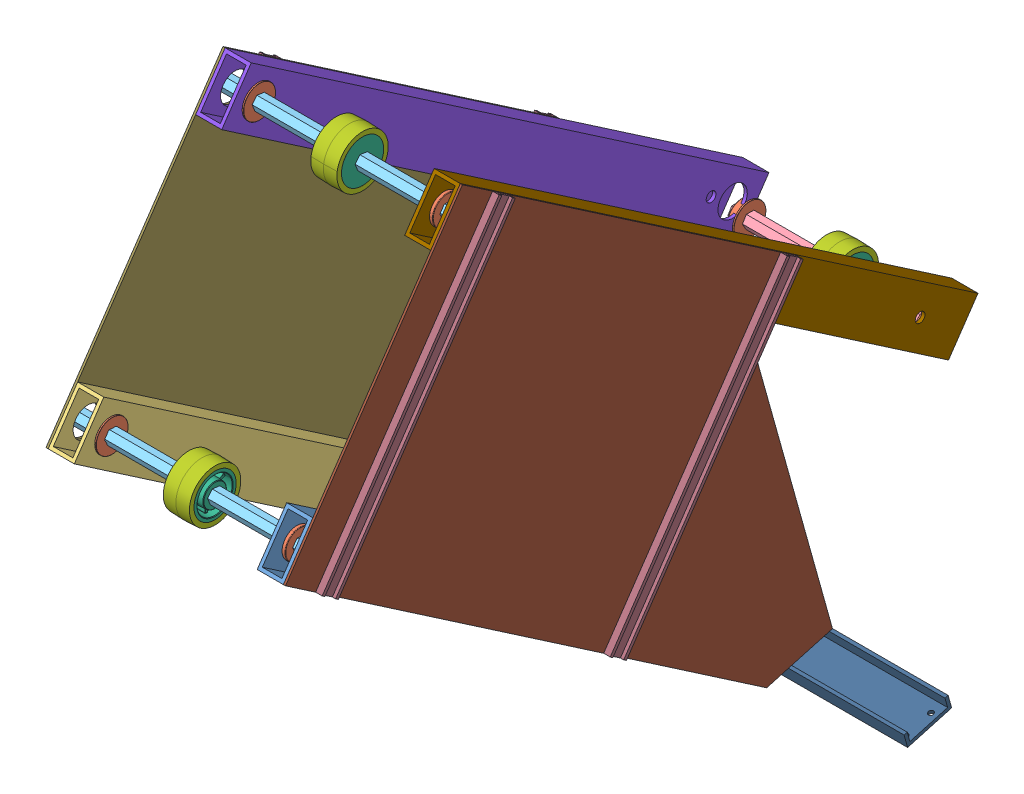
SolidWorks assembly Indexer, configuration Default. Lengths in mm.
Overall size (457.2 595.62 692.82).
37 component instances, 13 part files, 40 mates.
Components (placement in the parent):
- Bottom Indexer-1: Bottom Indexer [Default] at (229.7718 335.1654 356.4707) size (241.3 388.75 534.78)
  - Bottom Box Bar-1: Bottom Box Bar [Default] at (679.4899 930.1324 1666.1793) x (0 -0.825583 0.564281) z (0 -0.564281 -0.825583) size (50.8 25.4 609.6)
  - am-2986 FR8ZZ Hex Bearing.step-3: am-2986 FR8ZZ Hex Bearing.step [Default] at (660.4933 614.1774 1248.9284) x (0 0 1) z (-1 0 0) size (31.12 31.12 7.93)
  - am-2986 FR8ZZ Hex Bearing.step-4: am-2986 FR8ZZ Hex Bearing.step [Default] at (660.4933 894.8298 1659.5422) x (0 -0.924225 -0.381849) z (-1 0 0) size (31.12 31.12 7.93)
  - Bottom Box Bar B-1: Bottom Box Bar B [Default] at (476.2899 930.1324 1666.1793) x (0 -0.825583 0.564281) z (0 -0.564281 -0.825583) size (50.8 25.4 609.6)
  - am-2986 FR8ZZ Hex Bearing.step-9: am-2986 FR8ZZ Hex Bearing.step [Default] at (469.8866 894.8298 1659.5422) x (0 0 -1) z (1 0 0) size (31.12 31.12 7.93)
  - am-2986 FR8ZZ Hex Bearing.step-10: am-2986 FR8ZZ Hex Bearing.step [Default] at (469.8866 614.1774 1248.9284) x (0 0 -1) z (1 0 0) size (31.12 31.12 7.93)
  - bottom second rod-1: bottom second rod [Default] at (463.5899 614.1774 1248.9284) x (1 0 0) z (0 -0.866025 -0.5) size (203.2 12.7 14.66)
  - bottom first rod-2: bottom first rod [Default] at (438.1899 894.8298 1659.5422) x (1 0 0) z (0 -0.792804 0.609477) size (228.6 12.7 14.66)
  - am-3155 2IN 500Hex Stealth Wheel REV2.STEP-1: am-3155 2IN 500Hex Stealth Wheel REV2.STEP [Default] at (552.4899 606.4819 1277.5388) x (0 0.866025 -0.5) z (-1 0 0) size (57.25 57.25 25.4)
    - 2in Wheel Intergrated 0500 HEX Hub.STEP-1: 2in Wheel Intergrated 0500 HEX Hub.STEP [Default] at (20.955 20.955 -12.7) x (-0.866025 0.5 0) z (0 0 -1) size (41.91 41.91 25.4)
    - 2in Tread.STEP-1: 2in Tread.STEP [Default] at (20.955 20.955 -12.7) x (0 0 -1) z (1 0 0) size (25.4 50.8 50.8)
  - am-3155 2IN 500Hex Stealth Wheel REV2.STEP-2: am-3155 2IN 500Hex Stealth Wheel REV2.STEP [Default] at (577.8899 924.2456 1663.4241) x (0 -0.792804 0.609477) z (1 0 0) size (57.25 57.25 25.4)
    - 2in Wheel Intergrated 0500 HEX Hub.STEP-1: 2in Wheel Intergrated 0500 HEX Hub.STEP [Default] at (20.955 20.955 -12.7) x (-0.866025 0.5 0) z (0 0 -1) size (41.91 41.91 25.4)
    - 2in Tread.STEP-1: 2in Tread.STEP [Default] at (20.955 20.955 -12.7) x (0 0 -1) z (1 0 0) size (25.4 50.8 50.8)
- Top Box Bar-1: Top Box Bar [Default] at (706.0617 1474.9957 1879.3225) x (0 -0.825583 0.564281) z (0 -0.564281 -0.825583) size (50.8 25.4 609.6)
- Top Box Bar B-1: Top Box Bar B [Default] at (909.2617 1474.9957 1879.3225) x (0 -0.825583 0.564281) z (0 -0.564281 -0.825583) size (50.8 25.4 609.6)
- Indexer Bottom Bar-1: Indexer Bottom Bar [Default] at (566.3617 897.0934 1558.7521) x (1 0 0) z (0 -0.26972 0.962939) size (457.2 12.7 44.45)
- Top Indexer-1: Top Indexer [Default] at (0 -31.4192 24.5795) x (1 0 0) z (0 0.016887 0.999857) size (228.6 390.37 543.04)
  - am-2986 FR8ZZ Hex Bearing.step-1: am-2986 FR8ZZ Hex Bearing.step [Default] at (699.6584 1110.04 1390.3802) x (0 0 -1) z (1 0 0) size (31.12 31.12 7.93)
  - am-2986 FR8ZZ Hex Bearing.step-2: am-2986 FR8ZZ Hex Bearing.step [Default] at (890.265 1110.04 1390.3802) x (0 0 1) z (-1 0 0) size (31.12 31.12 7.93)
  - am-2986 FR8ZZ Hex Bearing.step-3: am-2986 FR8ZZ Hex Bearing.step [Default] at (699.6584 1439.6932 1872.6855) x (0 -0.924225 -0.381849) z (1 0 0) size (31.12 31.12 7.93)
  - am-2986 FR8ZZ Hex Bearing.step-4: am-2986 FR8ZZ Hex Bearing.step [Default] at (890.265 1439.6932 1872.6855) x (0 0 1) z (-1 0 0) size (31.12 31.12 7.93)
  - bottom first rod-1: bottom first rod [Default] at (667.9617 1439.6932 1872.6855) x (1 0 0) z (0 -0.924225 -0.381849) size (228.6 12.7 14.66)
  - bottom second rod-1: bottom second rod [Default] at (693.3617 1110.04 1390.3802) x (1 0 0) z (0 -0.866025 -0.5) size (203.2 12.7 14.66)
  - am-3155 2IN 500Hex Stealth Wheel REV2.STEP-1: am-3155 2IN 500Hex Stealth Wheel REV2.STEP [Default] at (782.2617 1131.0204 1411.3792) x (0 0 -1) z (-1 0 0) size (57.25 57.25 25.4)
    - 2in Wheel Intergrated 0500 HEX Hub.STEP-1: 2in Wheel Intergrated 0500 HEX Hub.STEP [Default] at (20.955 20.955 -12.7) x (-0.866025 0.5 0) z (0 0 -1) size (41.91 41.91 25.4)
    - 2in Tread.STEP-1: 2in Tread.STEP [Default] at (20.955 20.955 -12.7) x (0 0 -1) z (1 0 0) size (25.4 50.8 50.8)
  - am-3155 2IN 500Hex Stealth Wheel REV2.STEP-2: am-3155 2IN 500Hex Stealth Wheel REV2.STEP [Default] at (782.2617 1463.1971 1890.7227) x (0 -0.131421 -0.991327) z (-1 0 0) size (57.25 57.25 25.4)
    - 2in Wheel Intergrated 0500 HEX Hub.STEP-1: 2in Wheel Intergrated 0500 HEX Hub.STEP [Default] at (20.955 20.955 -12.7) x (-0.866025 0.5 0) z (0 0 -1) size (41.91 41.91 25.4)
    - 2in Tread.STEP-1: 2in Tread.STEP [Default] at (20.955 20.955 -12.7) x (0 0 -1) z (1 0 0) size (25.4 50.8 50.8)
- Indexer Side Wall-1: Indexer Side Wall [Default] at (909.2617 1265.2977 2022.65) x (0 0.825583 -0.564281) z (1 0 0) size (304.8 609.3 2.11)
- Indexer Side Wall B-1: Indexer Side Wall B [Default] at (678.5535 1265.2977 2022.65) x (0 0.825583 -0.564281) z (1 0 0) size (304.8 609.6 2.11)
- Connecting Bar-1: Connecting Bar [Default] at (911.3699 1263.5877 1570.018) x (0 -0.564281 -0.825583) z (0 -0.825583 0.564281) size (19.05 6.35 304.8)
- Connecting Bar-2: Connecting Bar [Default] at (678.5535 1252.8381 1554.2907) x (0 0.564281 0.825583) z (0 -0.825583 0.564281) size (19.05 6.35 304.8)
- Connecting Bar-3: Connecting Bar [Default] at (911.3699 1454.9728 1850.0276) x (0 -0.564281 -0.825583) z (0 -0.825583 0.564281) size (19.05 6.35 304.8)
- Connecting Bar-4: Connecting Bar [Default] at (678.5535 1435.5807 1821.6556) x (0 0.564281 0.825583) z (0 -0.825583 0.564281) size (19.05 6.35 304.8)
Mates (geometry in assembly coordinates):
- Coincident2: coincident aligned: plane of Bottom Indexer-1/Bottom Box Bar B-1 through (706.0617 921.3118 1519.3749) normal (1 0 0); plane of Top Box Bar-1 through (706.0617 1131.0098 1376.0474) normal (1 0 0)
- Distance1: distance = 203.2 mm: line of Bottom Indexer-1/Bottom Box Bar B-1 through (706.0617 921.3118 1519.3749) axis (0 0.564281 0.825583); line of Top Box Bar-1 through (706.0617 1089.0702 1404.7129) axis (0 0.564281 0.825583)
- Coincident4: coincident aligned: plane of Top Box Bar-1 through (706.0617 1131.0098 1376.0474) normal (0 0.825583 -0.564281); plane of Top Box Bar B-1 through (909.2617 1131.0098 1376.0474) normal (0 0.825583 -0.564281)
- Coincident6: coincident aligned: plane of Bottom Indexer-1/Bottom Box Bar-1 through (909.2617 921.3118 1519.3749) normal (1 0 0); plane of Top Box Bar B-1 through (909.2617 1131.0098 1376.0474) normal (1 0 0)
- Width1: width anti-aligned: plane of Indexer Bottom Bar-1 through (1023.5617 897.0934 1558.7521) normal (1 0 0); plane of Indexer Bottom Bar-1 through (566.3617 897.0934 1558.7521) normal (-1 0 0); plane of Bottom Indexer-1/Bottom Box Bar B-1 through (680.6617 921.3118 1519.3749) normal (-1 0 0); plane of Bottom Indexer-1/Bottom Box Bar-1 through (909.2617 921.3118 1519.3749) normal (1 0 0)
- Coincident9: coincident aligned: plane of Bottom Indexer-1/Bottom Box Bar-1 through (909.2617 1265.2977 2022.65) normal (0 0.564281 0.825583); plane of Top Box Bar B-1 through (909.2617 1474.9957 1879.3225) normal (0 0.564281 0.825583)
- InPlace1: in place: plane of Bottom Indexer-1/Bottom Box Bar-1 through (909.2617 921.3118 1519.3749) normal (1 0 0); plane of ? through (909.2617 0 0) normal (1 0 0); moOrthogonalPlaneRef_w of Bottom Indexer-1/Bottom Box Bar-1 through (909.2617 921.3118 1519.3749) normal (1 0 0); plane of ? through (909.2617 0 0) normal (0 1 0); plane of Bottom Indexer-1/Bottom Box Bar-1 through (909.2617 921.3118 1519.3749) normal (1 0 0); plane of ? through (909.2617 0 0) normal (0 0 -1); plane of Bottom Indexer-1/Bottom Box Bar-1 through (909.2617 921.3118 1519.3749) normal (1 0 0); unknown of Indexer Side Wall-1
- Coincident26: coincident aligned: plane of Bottom Indexer-1/Bottom Box Bar-1; plane of Indexer Side Wall-1
- Coincident27: coincident aligned: moOrthogonalPlaneRef_w of Bottom Indexer-1/Bottom Box Bar-1 through (909.2617 1265.2977 2022.65) normal (0 0.564281 0.825583); plane of Indexer Side Wall-1 through (909.2617 1265.2977 2022.65) normal (0 0.564281 0.825583)
- Coincident28: coincident anti-aligned: moOrthogonalPlaneRef_w of Bottom Indexer-1/Bottom Box Bar-1 through (909.2617 1265.2977 2022.65) normal (0 -0.825583 0.564281); plane of Indexer Side Wall-1 through (909.2617 1265.2977 2022.65) normal (0 0.825583 -0.564281)
- Coincident29: coincident anti-aligned: line of Bottom Indexer-1/Bottom Box Bar B-1 through (680.6617 903.4254 1583.2319) axis (0 0.564281 0.825583); line of Indexer Side Wall B-1 through (680.6617 1223.3581 2051.3155) axis (0 -0.564281 -0.825583)
- Coincident30: coincident anti-aligned: line of Bottom Indexer-1/Bottom Box Bar B-1 through (680.6617 1223.3581 2051.3155) axis (0 0.825583 -0.564281); line of Indexer Side Wall B-1 through (680.6617 1474.9957 1879.3225) axis (0 -0.825583 0.564281)
- Coincident32: coincident anti-aligned: line of Indexer Side Wall B-1 through (678.5535 1223.3581 2051.3155) axis (0 -0.564281 -0.825583); line of Connecting Bar-4 through (678.5535 1183.9431 1993.6486) axis (0 0.564281 0.825583)
- Coincident33: coincident anti-aligned: line of Indexer Side Wall B-1 through (678.5535 1223.3581 2051.3155) axis (0 -0.564281 -0.825583); line of Connecting Bar-2 through (678.5535 1001.2006 1726.2837) axis (0 0.564281 0.825583)
- Coincident34: coincident anti-aligned: plane of Indexer Side Wall B-1 through (678.5535 1265.2977 2022.65) normal (-1 0 0); plane of Connecting Bar-4 through (678.5535 1183.9431 1993.6486) normal (1 0 0)
- Coincident36: coincident anti-aligned: plane of Indexer Side Wall B-1 through (678.5535 1265.2977 2022.65) normal (-1 0 0); plane of Connecting Bar-2 through (678.5535 1001.2006 1726.2837) normal (1 0 0)
- Distance2: distance = 50.8 mm aligned: plane of Connecting Bar-4 through (678.5535 1194.6927 2009.3759) normal (0 0.564281 0.825583); plane of Top Box Bar-1 through (706.0617 1474.9957 1879.3225) normal (0 0.564281 0.825583)
- Distance3: distance = 215.9 mm aligned: plane of Connecting Bar-2 through (678.5535 1001.2006 1726.2837) normal (0 -0.564281 -0.825583); plane of Top Box Bar-1 through (706.0617 1131.0098 1376.0474) normal (0 -0.564281 -0.825583)
- Coincident39: coincident anti-aligned: plane of Indexer Side Wall-1 through (911.3699 1265.2977 2022.65) normal (1 0 0); plane of Connecting Bar-1 through (911.3699 1011.9501 1742.011) normal (-1 0 0)
- Coincident40: coincident anti-aligned: plane of Indexer Side Wall-1 through (911.3699 1265.2977 2022.65) normal (1 0 0); plane of Connecting Bar-3 through (911.3699 1203.3352 2022.0206) normal (-1 0 0)
- Coincident41: coincident aligned: line of Indexer Side Wall-1 through (911.3699 1223.3581 2051.3155) axis (0 -0.564281 -0.825583); line of Connecting Bar-3 through (911.3699 1203.3352 2022.0206) axis (0 -0.564281 -0.825583)
- Coincident42: coincident aligned: line of Indexer Side Wall-1 through (911.3699 1223.3581 2051.3155) axis (0 -0.564281 -0.825583); line of Connecting Bar-1 through (911.3699 1011.9501 1742.011) axis (0 -0.564281 -0.825583)
- Coincident44: coincident aligned: plane of Connecting Bar-1 through (911.3699 1011.9501 1742.011) normal (0 0.564281 0.825583); plane of Connecting Bar-2 through (678.5535 1011.9501 1742.011) normal (0 0.564281 0.825583)
- Coincident45: coincident anti-aligned: plane of Top Box Bar-1 through (706.0617 1131.0098 1376.0474) normal (1 0 0); plane of Top Indexer-1/am-2986 FR8ZZ Hex Bearing.step-1 through (706.0617 1101.7063 1382.0479) normal (-1 0 0)
- Coincident48: coincident anti-aligned: plane of Top Box Bar B-1 through (883.8617 1131.0098 1376.0474) normal (-1 0 0); plane of Top Indexer-1/am-2986 FR8ZZ Hex Bearing.step-2 through (883.8617 1102.1781 1409.9839) normal (1 0 0)
- Concentric7: concentric aligned: cylinder of Top Box Bar-1 through (706.0617 1439.6932 1872.6855) axis (-1 0 0) radius 14.2875; cylinder of Top Indexer-1/am-2986 FR8ZZ Hex Bearing.step-3 through (707.5857 1439.6932 1872.6855) axis (-1 0 0) radius 14.2875
- Coincident49: coincident anti-aligned: plane of Top Box Bar-1 through (706.0617 1131.0098 1376.0474) normal (1 0 0); plane of Top Indexer-1/am-2986 FR8ZZ Hex Bearing.step-3 through (706.0617 1426.6935 1867.5699) normal (-1 0 0)
- Concentric8: concentric anti-aligned: cylinder of Top Box Bar B-1 through (887.0367 1439.6932 1872.6855) axis (-1 0 0) radius 14.2875; cylinder of Top Indexer-1/am-2986 FR8ZZ Hex Bearing.step-4 through (882.3377 1439.6932 1872.6855) axis (1 0 0) radius 14.2875
- Coincident52: coincident anti-aligned: plane of Top Box Bar B-1 through (883.8617 1131.0098 1376.0474) normal (-1 0 0); plane of Top Indexer-1/am-2986 FR8ZZ Hex Bearing.step-4 through (883.8617 1439.9291 1886.6535) normal (1 0 0)
- Width4: width anti-aligned: plane of Top Indexer-1/bottom second rod-1 through (896.5617 1101.9422 1396.0159) normal (1 0 0); plane of Top Indexer-1/bottom second rod-1 through (693.3617 1101.9422 1396.0159) normal (-1 0 0); plane of Top Box Bar-1 through (680.6617 1131.0098 1376.0474) normal (-1 0 0); plane of Top Box Bar B-1 through (909.2617 1131.0098 1376.0474) normal (1 0 0)
- Width5: width anti-aligned: plane of Top Indexer-1/am-3155 2IN 500Hex Stealth Wheel REV2.STEP-1/2in Tread.STEP-1 through (807.6617 1077.0154 1396.4809) normal (1 0 0); plane of Top Indexer-1/am-3155 2IN 500Hex Stealth Wheel REV2.STEP-1/2in Tread.STEP-1 through (782.2617 1077.0154 1396.4809) normal (-1 0 0); plane of Top Box Bar B-1 through (883.8617 1131.0098 1376.0474) normal (-1 0 0); plane of Top Box Bar-1 through (706.0617 1131.0098 1376.0474) normal (1 0 0)
- Coincident53: coincident aligned: plane of Bottom Indexer-1/Bottom Box Bar B-1 through (706.0617 921.3118 1519.3749) normal (1 0 0); plane of Top Indexer^Indexer-1/Top Box Bar-1 through (706.0617 1116.677 1355.0776) normal (1 0 0)
- Distance5: distance = 203.2 mm: line of Bottom Indexer-1/Bottom Box Bar B-1 through (706.0617 921.3118 1519.3749) axis (0 0.564281 0.825583); line of Top Indexer^Indexer-1/Top Box Bar-1 through (706.0617 1074.7374 1383.7431) axis (0 0.564281 0.825583)
- Coincident54: coincident aligned: plane of Top Indexer^Indexer-1/Top Box Bar-1 through (706.0617 1116.677 1355.0776) normal (0 0.825583 -0.564281); plane of Top Box Bar B-1 through (909.2617 1131.0098 1376.0474) normal (0 0.825583 -0.564281)
- Coincident55: coincident aligned: plane of Top Indexer^Indexer-1/Top Box Bar-1 through (706.0617 1116.677 1355.0776) normal (0 -0.564281 -0.825583); plane of Top Box Bar B-1 through (909.2617 1131.0098 1376.0474) normal (0 -0.564281 -0.825583)
- Distance6: distance = 50.8 mm aligned: plane of Connecting Bar-4 through (678.5535 1194.6927 2009.3759) normal (0 0.564281 0.825583); plane of Top Indexer^Indexer-1/Top Box Bar-1 through (706.0617 1474.9957 1879.3225) normal (0 0.564281 0.825583)
- Distance7: distance = 215.9 mm aligned: plane of Connecting Bar-2 through (678.5535 1001.2006 1726.2837) normal (0 -0.564281 -0.825583); plane of Top Indexer^Indexer-1/Top Box Bar-1 through (706.0617 1116.677 1355.0776) normal (0 -0.564281 -0.825583)
- Coincident56: coincident anti-aligned: line of Bottom Indexer-1/Bottom Box Bar-1 through (883.8617 921.3118 1519.3749) axis (1 0 0); line of Indexer Bottom Bar-1 through (1023.5617 921.3118 1519.3749) axis (-1 0 0)
- Coincident57: coincident anti-aligned: plane of Bottom Indexer-1/Bottom Box Bar B-1 through (706.0617 903.4254 1583.2319) normal (0 -0.962939 -0.26972); plane of Indexer Bottom Bar-1 through (1023.5617 909.3228 1562.1775) normal (0 0.962939 0.26972)
- Coincident58: coincident aligned: plane of Top Box Bar-1 through (706.0617 1474.9957 1879.3225) normal (0 0.564281 0.825583); plane of Top Box Bar B-1 through (909.2617 1474.9957 1879.3225) normal (0 0.564281 0.825583)
